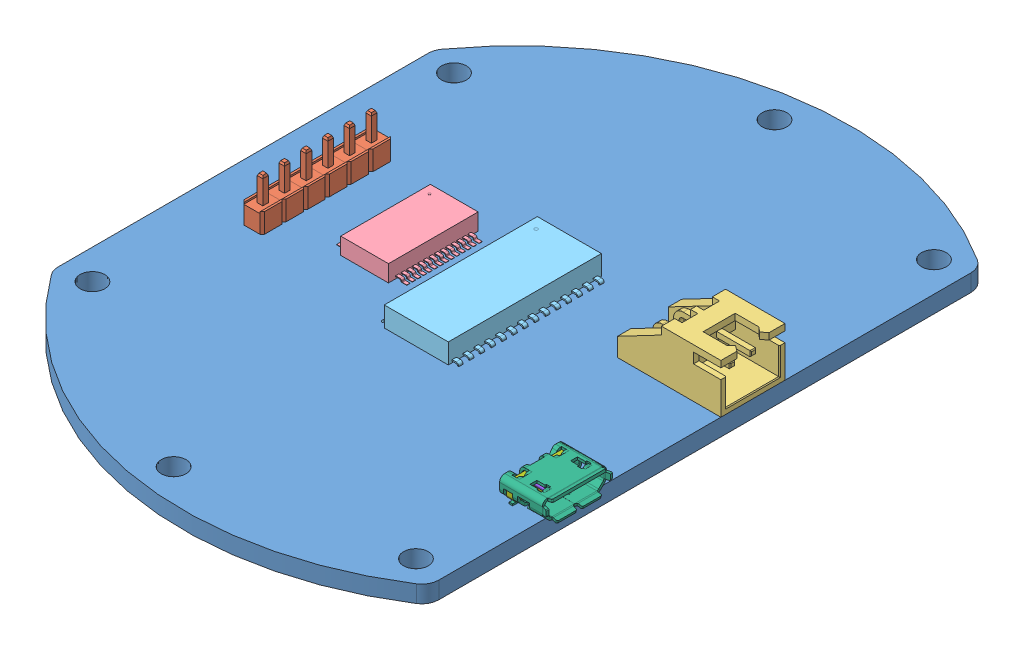
SolidWorks assembly PCB_assy, configuration Default. Lengths in mm.
Overall size (55.12 11.75 78).
21 component instances, 9 part files, 19 mates.
Components (placement in the parent):
- PCB-1: PCB [Default] at origin size (54 2 78)
- 6x_Male_Pin_2.54_mm.STEP-1: 6x_Male_Pin_2.54_mm.STEP [Default] at (-13.0414 9.5562 -3.2116) x (0 0 -1) z (-1 0 0) size (15.24 11.1 2.4)
  - 1_Male_Pin_2.54_mm.STEP-1: 1_Male_Pin_2.54_mm.STEP [Default] at (3.8763 2.2562 11.0637) size (2.54 11.1 2.4)
  - 1_Male_Pin_2.54_mm.STEP-2: 1_Male_Pin_2.54_mm.STEP [Default] at (1.3363 2.2562 11.0637) size (2.54 11.1 2.4)
  - 1_Male_Pin_2.54_mm.STEP-3: 1_Male_Pin_2.54_mm.STEP [Default] at (-1.2037 2.2562 11.0637) size (2.54 11.1 2.4)
  - 1_Male_Pin_2.54_mm.STEP-4: 1_Male_Pin_2.54_mm.STEP [Default] at (-3.7437 2.2562 11.0637) size (2.54 11.1 2.4)
  - 1_Male_Pin_2.54_mm.STEP-5: 1_Male_Pin_2.54_mm.STEP [Default] at (-6.2837 2.2562 11.0637) size (2.54 11.1 2.4)
  - 1_Male_Pin_2.54_mm.STEP-6: 1_Male_Pin_2.54_mm.STEP [Default] at (-8.8237 2.2562 11.0637) size (2.54 11.1 2.4)
- JST 2pin Right Receptacle-1: JST 2pin Right Receptacle [Default] at (21.4 1.4 5.6261) x (0 0 -1) z (0 1 0) size (7.5 12.1 8.58)
- SSOP28_MC_MCH-1: SSOP28_MC_MCH [Default] at (-13.8397 1.949 -1.2783) x (1 0 0) z (0 1 0) size (8.23 10.49 2.03)
- SOIC28-W_MC_MCH-1: SOIC28-W_MC_MCH [Default] at (-2.983 1.695 -0.1782) x (1 0 0) z (0 1 0) size (10.31 17.91 2.65)
- micro_usb_connector-1: micro_usb_connector [Default] at (19.5 2 15.7597) x (1 0 0) z (0 1 0) size (5.84 7.77 3.4)
  - shield.stp-1: shield.stp [Default] at origin size (5.84 7.77 3.4)
  - socket_housing.stp-1: socket_housing.stp [Default] at origin size (4.25 6.85 2.15)
  - socket_plate.stp-1: socket_plate.stp [Default] at origin size (3.38 6.8 0.31)
  - terminal.stp-1: terminal.stp [Default] at origin size (3.22 0.35 1.72)
  - terminal.stp-2: terminal.stp [Default] at (0 -1.3 0) size (3.22 0.35 1.72)
  - terminal.stp-3: terminal.stp [Default] at (0 -0.65 0) size (3.22 0.35 1.72)
  - terminal.stp-4: terminal.stp [Default] at (0 0.65 0) size (3.22 0.35 1.72)
  - terminal.stp-5: terminal.stp [Default] at (0 1.3 0) size (3.22 0.35 1.72)
- PCB-2: PCB [Default] at (0 12 0) x (1 0 0) z (0 0 -1) size (54 2 78) (hidden)
Mates (geometry in assembly coordinates):
- Coincident1: coincident anti-aligned: plane of PCB2-1 through (0 2 0) normal (0 1 0); plane of 6x_Male_Pin_2.54_mm.STEP-1/1_Male_Pin_2.54_mm.STEP-5 through (-24.1051 2 3.0721) normal (0 -1 0)
- Parallel1: parallel aligned: plane of PCB2-1 through (-32 2 3.5) normal (0 0 1); plane of 6x_Male_Pin_2.54_mm.STEP-1/1_Male_Pin_2.54_mm.STEP-6
- Coincident2: coincident anti-aligned: plane of PCB2-1 through (0 2 0) normal (0 1 0); plane of JST 2pin Right Receptacle.step-1 through (15.05 2 -1.8739) normal (0 -1 0)
- Parallel2: parallel: plane of PCB2-1 through (-32 2 3.5) normal (0 0 1); plane of JST 2pin Right Receptacle.step-1
- Coincident3: coincident anti-aligned: plane of PCB2-1 through (0 2 0) normal (0 1 0); plane of SSOP28_MC_MCH.step-1 through (-16.6337 2 -6.5233) normal (0 -1 0)
- Coincident4: coincident anti-aligned: plane of PCB2-1 through (0 2 0) normal (0 1 0); plane of SOIC28-W_MC_MCH.step-1 through (-6.729 2 -9.1322) normal (0 -1 0)
- Parallel3: parallel aligned: plane of PCB2-1 through (22 2 32.2025) normal (1 0 0); plane of SOIC28-W_MC_MCH.step-1 through (0.763 2 8.7758) normal (1 0 0)
- Parallel4: parallel aligned: plane of PCB2-1 through (22 2 32.2025) normal (1 0 0); plane of SSOP28_MC_MCH.step-1 through (-11.0457 2 3.9667) normal (1 0 0)
- Coincident5: coincident anti-aligned: plane of PCB2-1 through (0 2 0) normal (0 1 0); plane of micro_usb_connector.stp-1/shield.stp-1 through (20 2 24.3179) normal (0 -1 0)
- Coincident6: coincident aligned: plane of PCB2-1 through (-32 2 3.5) normal (0 0 1); plane of JST 2pin Right Receptacle.step-1
- Coincident7: coincident aligned: plane of PCB2-1 through (-32 2 3.5) normal (0 0 1); plane of micro_usb_connector.stp-1/shield.stp-1
- Distance1: distance = 8 mm anti-aligned: plane of PCB2-1 through (0 2 0) normal (0 1 0); plane of PCB2-2 through (0 10 0) normal (0 -1 0)
- Concentric1: concentric anti-aligned: cylinder of PCB2-1 through (0 2 0) axis (0 -1 0) radius 39; cylinder of PCB2-2 through (0 10 0) axis (0 1 0) radius 39
- Coincident8: coincident aligned: plane of PCB2-1 through (-32 2 -22.2935) normal (-1 0 0); plane of PCB2-2 through (-32 10 22.2935) normal (-1 0 0)
- Parallel5: parallel aligned: plane of PCB2-1 through (-32 2 -22.2935) normal (-1 0 0); plane of 6x_Male_Pin_2.54_mm.STEP-1/1_Male_Pin_2.54_mm.STEP-6 through (-25.6301 2 4.0171) normal (-1 0 0)
- Parallel6: parallel aligned: plane of PCB2-1 through (22 2 32.2025) normal (1 0 0); plane of JST 2pin Right Receptacle.step-1 through (22 4.875 -5.6239) normal (1 0 0)
- Parallel7: parallel aligned: plane of PCB2-1 through (22 2 32.2025) normal (1 0 0); plane of micro_usb_connector.stp-1/socket_housing.stp-1 through (19 3.225 15.7597) normal (1 0 0)
- Distance2: distance = 3 mm aligned: plane of micro_usb_connector.stp-1/socket_housing.stp-1 through (19 3.225 15.7597) normal (1 0 0); plane of PCB2-1 through (22 2 32.2025) normal (1 0 0)
- Distance3: distance = 0 mm aligned: plane of JST 2pin Right Receptacle.step-1 through (22 4.875 -5.6239) normal (1 0 0); plane of PCB2-1 through (22 2 32.2025) normal (1 0 0)
